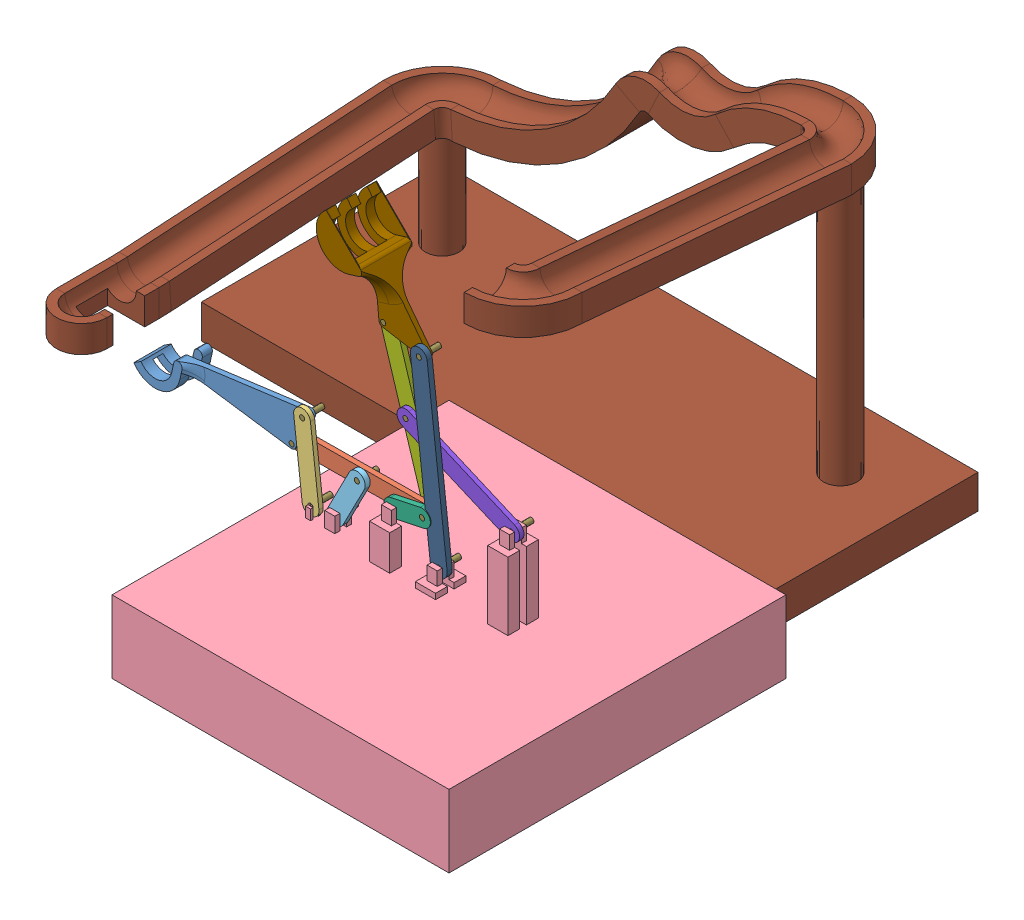
SolidWorks assembly 組合件1-1, configuration 預設. Lengths in mm.
Overall size (173.5 106.47 171.5).
23 component instances, 12 part files, 41 mates.
Components (placement in the parent):
- 第一大三角-1: 第一大三角 [預設] at (-79.4674 21.0474 -1.27) x (0.99118 0.132525 0) z (0 0 1) size (51.89 11.35 9.41)
- 38.69-1: 38.69 [預設] at (-27.885 16.6004 -2.77) x (-0.999961 -0.008814 0) z (0 0 1) size (43.68 5 1.5)
- 21.59-1: 21.59 [預設] at (-41.595 15.2214 0.115) x (-0.116552 0.993185 0) z (0 0 1) size (26.59 5 1.27)
- 大地板-1: 大地板 [預設] at origin size (100 45.67 100)
- 13.62-1: 13.62 [預設] at (-31.0109 10.5502 -1.27) x (0.459019 0.888427 0) z (0 0 1) size (18.62 5 1.5)
- 8.99-1: 8.99 [預設] at (-12.9402 15.8354 -1.27) x (-0.978107 -0.208103 0) z (0 0 1) size (13.99 5 1.5)
- 44.72-1: 44.72 [預設] at (-15.1524 38.1319 -4.27) x (-0.295562 0.955323 0) z (0 0 1) size (49.72 5 1.5)
- 34.16-1: 34.16 [預設] at (0.5454 31.4009 -2.87) x (0.919075 -0.394083 0) z (0 0 1) size (39.16 5 1.3)
- 第二大三角-1: 第二大三角 [預設] at (-42.4428 72.9237 -2.87) x (0.903813 -0.427927 0) z (0 0 1) size (34.96 20.73 16.35)
- 51.61-1: 51.61 [預設] at (-6.7127 31.7828 -1.47) x (0.115322 -0.993328 0) z (0 0 1) size (56.61 5 1.5)
- 軌道-1: 軌道 [預設] at (18 85 -14) size (159 105 132.01)
- 銷-1: 銷 [預設] at (-47.2263 16.4299 -3.52) size (1.5 1.5 6)
- 銷-2: 銷 [預設] at (-42.8532 25.9429 -2.25) size (1.5 1.5 6)
- 銷-3: 銷 [預設] at (-8.5437 16.7708 -3.52) size (1.5 1.5 6)
- 銷-4: 銷 [預設] at (-40.3368 4.5 -2.25) size (1.5 1.5 6)
- 銷-5: 銷 [預設] at (-27.885 16.6004 -3.52) size (1.5 1.5 6)
- 銷-6: 銷 [預設] at (-15.1524 38.1319 -5.22) size (1.5 1.5 6)
- 銷-7: 銷 [預設] at (-21.7612 59.4929 -5.22) size (1.5 1.5 6)
- 銷-8: 銷 [預設] at (-9.6886 57.4157 -3.72) size (1.5 1.5 6)
- 銷-9: 銷 [預設] at (-34.1368 4.5 -3.52) size (1.5 1.5 6)
- 銷-10: 銷 [預設] at (-17.3368 14.9 -3.52) size (1.5 1.5 6)
- 銷-11: 銷 [預設] at (-3.7368 6.15 -3.72) size (1.5 1.5 6)
- 銷-12: 銷 [預設] at (16.2432 24.67 -5.22) size (1.5 1.5 6)
Mates (geometry in assembly coordinates):
- 同軸心3: concentric aligned: cylinder of 21.59-1 through (-40.3368 4.5 0.75) axis (0 0 -1) radius 0.75; cylinder of 大地板-1 through (-40.3368 4.5 0.75) axis (0 0 -1) radius 0.75
- 重合/共線/共點3: coincident anti-aligned: plane of 21.59-1 through (-40.3368 4.5 0.75) normal (0 0 1); plane of 大地板-1 through (0 0 0.75) normal (0 0 -1)
- 重合/共線/共點4: coincident anti-aligned: plane of 第一大三角-1 through (-79.4674 21.0474 -0.52) normal (0 0 1); plane of 21.59-1 through (-40.3368 4.5 -0.52) normal (0 0 -1)
- 同軸心4: concentric anti-aligned: cylinder of 第一大三角-1 through (-42.8532 25.9429 -12.02) axis (0 0 1) radius 0.75; cylinder of 21.59-1 through (-42.8532 25.9429 0.75) axis (0 0 -1) radius 0.75
- 重合/共線/共點5: coincident anti-aligned: plane of 第一大三角-1 through (-79.4674 21.0474 -2.02) normal (0 0 -1); plane of 38.69-1 through (-8.5437 16.7708 -2.02) normal (0 0 1)
- 同軸心5: concentric anti-aligned: cylinder of 第一大三角-1 through (-47.2263 16.4299 -12.02) axis (0 0 1) radius 0.75; cylinder of 38.69-1 through (-47.2263 16.4299 -2.02) axis (0 0 -1) radius 0.75
- 重合/共線/共點6: coincident anti-aligned: plane of 38.69-1 through (-8.5437 16.7708 -2.02) normal (0 0 1); plane of 13.62-1 through (-34.1368 4.5 -2.02) normal (0 0 -1)
- 同軸心6: concentric aligned: cylinder of 大地板-1 through (-34.1368 4.5 0.25) axis (0 0 -1) radius 0.75; cylinder of 13.62-1 through (-34.1368 4.5 -0.52) axis (0 0 -1) radius 0.75
- 同軸心7: concentric aligned: cylinder of 38.69-1 through (-27.885 16.6004 -2.02) axis (0 0 -1) radius 0.75; cylinder of 13.62-1 through (-27.885 16.6004 -0.52) axis (0 0 -1) radius 0.75
- 重合/共線/共點10: coincident anti-aligned: plane of 38.69-1 through (-8.5437 16.7708 -2.02) normal (0 0 1); plane of 8.99-1 through (-8.5437 16.7708 -2.02) normal (0 0 -1)
- 同軸心8: concentric aligned: cylinder of 38.69-1 through (-8.5437 16.7708 -2.02) axis (0 0 -1) radius 0.75; cylinder of 8.99-1 through (-8.5437 16.7708 -0.52) axis (0 0 -1) radius 0.75
- 同軸心9: concentric aligned: cylinder of 大地板-1 through (-17.3368 14.9 0.75) axis (0 0 -1) radius 0.75; cylinder of 8.99-1 through (-17.3368 14.9 -0.52) axis (0 0 -1) radius 0.75
- 重合/共線/共點11: coincident anti-aligned: plane of 38.69-1 through (-8.5437 16.7708 -3.52) normal (0 0 -1); plane of 44.72-1 through (-8.5437 16.7708 -3.52) normal (0 0 1)
- 同軸心10: concentric aligned: cylinder of 38.69-1 through (-8.5437 16.7708 -2.02) axis (0 0 -1) radius 0.75; cylinder of 44.72-1 through (-8.5437 16.7708 -3.52) axis (0 0 -1) radius 0.75
- 重合/共線/共點12: coincident anti-aligned: plane of 44.72-1 through (-8.5437 16.7708 -3.52) normal (0 0 1); plane of 34.16-1 through (-15.1524 38.1319 -3.52) normal (0 0 -1)
- 同軸心11: concentric aligned: cylinder of 44.72-1 through (-15.1524 38.1319 -3.52) axis (0 0 -1) radius 0.75; cylinder of 34.16-1 through (-15.1524 38.1319 -2.22) axis (0 0 -1) radius 0.75
- 同軸心12: concentric aligned: cylinder of 大地板-1 through (16.2432 24.67 0.3713) axis (0 0 -1) radius 0.75; cylinder of 34.16-1 through (16.2432 24.67 -2.22) axis (0 0 -1) radius 0.75
- 重合/共線/共點13: coincident anti-aligned: plane of 44.72-1 through (-8.5437 16.7708 -3.52) normal (0 0 1); plane of 第二大三角-1 through (-9.6886 57.4157 -3.52) normal (0 0 -1)
- 同軸心13: concentric aligned: cylinder of 44.72-1 through (-21.7612 59.4929 -3.52) axis (0 0 -1) radius 0.75; cylinder of 第二大三角-1 through (-21.7612 59.4929 -2.22) axis (0 0 -1) radius 0.75
- 重合/共線/共點14: coincident anti-aligned: plane of 第二大三角-1 through (-9.6886 57.4157 -2.22) normal (0 0 1); plane of 51.61-1 through (-9.6886 57.4157 -2.22) normal (0 0 -1)
- 同軸心14: concentric aligned: cylinder of 第二大三角-1 through (-9.6886 57.4157 -2.22) axis (0 0 -1) radius 0.75; cylinder of 51.61-1 through (-9.6886 57.4157 -0.72) axis (0 0 -1) radius 0.75
- 同軸心15: concentric aligned: cylinder of 大地板-1 through (-3.7368 6.15 0.75) axis (0 0 -1) radius 0.75; cylinder of 51.61-1 through (-3.7368 6.15 -0.72) axis (0 0 -1) radius 0.75
- 重合/共線/共點15: coincident aligned: plane of 大地板-1 through (0 0 0) normal (0 1 0); plane of assembly through (0 0 0) normal (0 1 0)
- 重合/共線/共點16: coincident aligned: plane of 大地板-1 through (0 0 0) normal (0 0 1); plane of assembly through (0 0 0) normal (0 0 1)
- 重合/共線/共點17: coincident aligned: plane of 大地板-1 through (0 0 0) normal (1 0 0); plane of assembly through (0 0 0) normal (1 0 0)
- 平行相距2: distance = 85 mm aligned: plane of assembly through (0 0 0) normal (0 1 0); plane of 軌道-1 through (18 85 -14) normal (0 1 0)
- 平行相距3: distance = 14 mm aligned: plane of assembly through (0 0 0) normal (0 0 1); plane of 軌道-1 through (18 85 -14) normal (0 0 1)
- 平行相距4: distance = 18 mm aligned: plane of assembly through (0 0 0) normal (1 0 0); plane of 軌道-1 through (18 85 -14) normal (1 0 0)
- 重合/共線/共點21: coincident aligned: plane of 第一大三角-1 through (-79.4674 21.0474 -0.52) normal (0 0 1); plane of 銷-1 through (-47.2263 16.4299 -0.52) normal (0 0 1)
- 重合/共線/共點22: coincident aligned: circle of 第一大三角-1; circle of 銷-1
- 重合/共線/共點24: coincident aligned: circle of 21.59-1; circle of 銷-2
- 重合/共線/共點26: coincident aligned: circle of 13.62-1; circle of 銷-5
- 重合/共線/共點27: coincident aligned: circle of 8.99-1; circle of 銷-3
- 重合/共線/共點28: coincident aligned: circle of 34.16-1; circle of 銷-6
- 重合/共線/共點29: coincident aligned: circle of 第二大三角-1; circle of 銷-7
- 重合/共線/共點30: coincident aligned: circle of 51.61-1; circle of 銷-8
- 重合/共線/共點31: coincident aligned: circle of 大地板-1; circle of 銷-4
- 重合/共線/共點32: coincident aligned: circle of 13.62-1; circle of 銷-9
- 重合/共線/共點33: coincident aligned: circle of 8.99-1; circle of 銷-10
- 重合/共線/共點34: coincident aligned: circle of 51.61-1; circle of 銷-11
- 重合/共線/共點35: coincident aligned: circle of 34.16-1; circle of 銷-12
